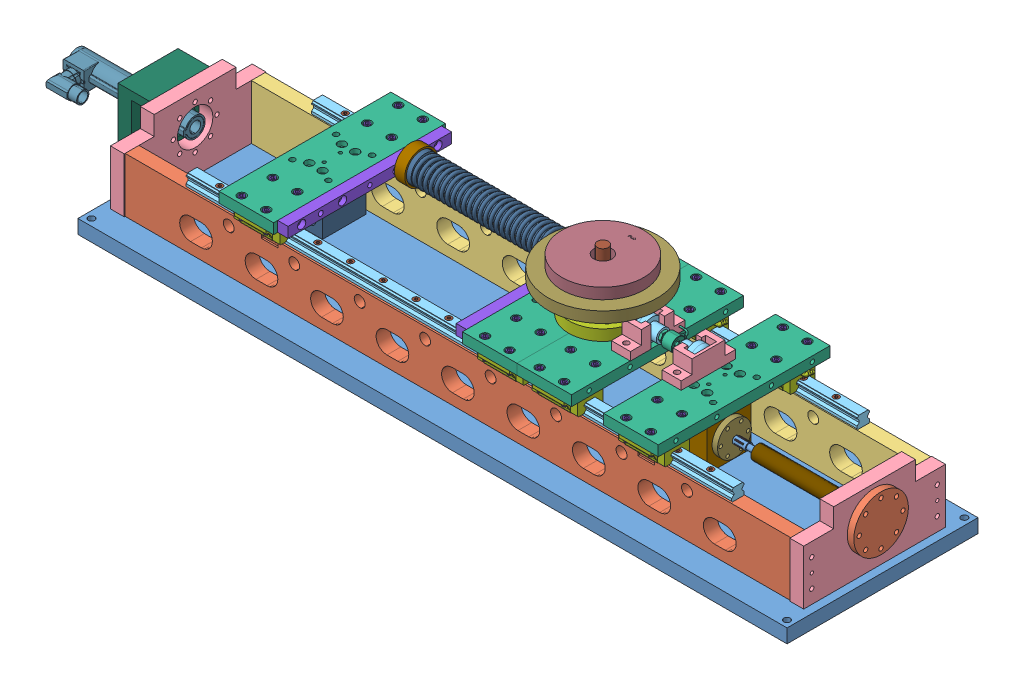
SolidWorks assembly Montagem global 2, configuration Valor predeterminado. Lengths in mm.
Overall size (1476 290.42 350).
128 component instances, 38 part files, 138 mates.
Components (placement in the parent):
- Breadboard-1: Breadboard [Default] at (-231.8815 -89.5152 1800) size (1800 58 900) (hidden)
- Base_global-1: Base_global [Valor predeterminado] at (-456.8815 -71.8152 1800) x (0 0 1) z (-1 0 0) size (350 25.4 1300)
- Lateral_comunha-1: Lateral_comunha [Valor predeterminado] at (-456.8815 -9.1152 1913) x (0 0 -1) z (1 0 0) size (25.4 100 1220)
- Lateral_semunha-1: Lateral_semunha [Valor predeterminado] at (-456.8815 -9.1152 1687) x (0 0 1) z (-1 0 0) size (25.4 100 1220)
- Cantoneira-1: Cantoneira [Valor predeterminado] at (-1079.5815 20.8848 1800) x (0 0 1) z (-1 0 0) size (260 135 25.4)
- Cantoneira-2: Cantoneira [Valor predeterminado] at (165.8185 20.8848 1800) x (0 0 1) z (-1 0 0) size (260 135 25.4)
- KR25 trilho1000-1: KR25 trilho1000 [Valor predeterminado] at (43.1185 42.034 1696.3931) x (0 1 0) z (-1 0 0) size (21.9 23 1000)
- KR25 trilho1000-2: KR25 trilho1000 [Valor predeterminado] at (43.1365 42.034 1926.3931) x (0 1 0) z (-1 0 0) size (21.9 23 1000)
- Montangem_atuador_linear-1: Montangem_atuador_linear [Valor predeterminado] at (-570.0811 33.0421 1784.6923) x (0 0 -1) z (1 0 0) size (315 119.02 108.05)
  - Montagem_plataforma_patins-1: Montagem_plataforma_patins [Valor predeterminado] at (20.5344 58.2954 310) size (315 49.52 108.05)
    - Plataforma-1: Plataforma [Valor predeterminado] at (-35.8421 -14.4528 149.5555) size (315 19.02 100)
    - KRH25-FL-N-Z0-1: KRH25-FL-N-Z0 [Valor predeterminado] at (79.1579 -44.9528 191.5555) x (0 0 -1) z (0 1 0) size (96 70 30.5)
    - KRH25-FL-N-Z0-2: KRH25-FL-N-Z0 [Valor predeterminado] at (-150.8421 -44.9528 107.5055) x (0 0 1) z (0 1 0) size (96 70 30.5)
    - Allen_M6x30-1: Allen_M6x30 [Valor predeterminado] at (107.6579 -33.4328 127.0555) x (1 0 0) z (0 1 0) size (10 10 38)
    - Allen_M6x30-2: Allen_M6x30 [Valor predeterminado] at (107.6579 -33.4328 172.0555) x (1 0 0) z (0 1 0) size (10 10 38)
    - Allen_M6x30-3: Allen_M6x30 [Valor predeterminado] at (-179.3421 -33.4328 172.0055) x (1 0 0) z (0 1 0) size (10 10 38)
    - Allen_M6x30-4: Allen_M6x30 [Valor predeterminado] at (-122.3421 -33.4328 172.0055) x (1 0 0) z (0 1 0) size (10 10 38)
    - Allen_M6x30-5: Allen_M6x30 [Valor predeterminado] at (-179.3421 -33.4328 127.0055) x (1 0 0) z (0 1 0) size (10 10 38)
    - Allen_M6x30-6: Allen_M6x30 [Valor predeterminado] at (-122.3421 -33.4328 127.0055) x (1 0 0) z (0 1 0) size (10 10 38)
    - Allen_M6x30-7: Allen_M6x30 [Valor predeterminado] at (50.6579 -33.4328 127.0555) x (1 0 0) z (0 1 0) size (10 10 38)
    - Allen_M6x30-8: Allen_M6x30 [Valor predeterminado] at (50.6579 -33.4328 172.0555) x (1 0 0) z (0 1 0) size (10 10 38)
  - Bloco_transmissão-1: Bloco_transmissão [Valor predeterminado] at (-15.3077 -14.7573 459.5555) size (80 100 44.45)
- Montagem_plataforma_patins-1: Montagem_plataforma_patins [Valor predeterminado] at (-219.97 91.3376 1835.8421) x (0 0 1) z (-1 0 0) size (315 49.52 108.05)
  - Plataforma-1: Plataforma [Valor predeterminado] at (-35.8421 -14.4528 149.5555) size (315 19.02 100)
  - KRH25-FL-N-Z0-1: KRH25-FL-N-Z0 [Valor predeterminado] at (79.1579 -44.9528 191.5555) x (0 0 -1) z (0 1 0) size (96 70 30.5)
  - KRH25-FL-N-Z0-2: KRH25-FL-N-Z0 [Valor predeterminado] at (-150.8421 -44.9528 107.5055) x (0 0 1) z (0 1 0) size (96 70 30.5)
  - Allen_M6x30-1: Allen_M6x30 [Valor predeterminado] at (107.6579 -33.4328 127.0555) x (1 0 0) z (0 1 0) size (10 10 38)
  - Allen_M6x30-2: Allen_M6x30 [Valor predeterminado] at (107.6579 -33.4328 172.0555) x (1 0 0) z (0 1 0) size (10 10 38)
  - Allen_M6x30-3: Allen_M6x30 [Valor predeterminado] at (-179.3421 -33.4328 172.0055) x (1 0 0) z (0 1 0) size (10 10 38)
  - Allen_M6x30-4: Allen_M6x30 [Valor predeterminado] at (-122.3421 -33.4328 172.0055) x (1 0 0) z (0 1 0) size (10 10 38)
  - Allen_M6x30-5: Allen_M6x30 [Valor predeterminado] at (-179.3421 -33.4328 127.0055) x (1 0 0) z (0 1 0) size (10 10 38)
  - Allen_M6x30-6: Allen_M6x30 [Valor predeterminado] at (-122.3421 -33.4328 127.0055) x (1 0 0) z (0 1 0) size (10 10 38)
  - Allen_M6x30-7: Allen_M6x30 [Valor predeterminado] at (50.6579 -33.4328 127.0555) x (1 0 0) z (0 1 0) size (10 10 38)
  - Allen_M6x30-8: Allen_M6x30 [Valor predeterminado] at (50.6579 -33.4328 172.0555) x (1 0 0) z (0 1 0) size (10 10 38)
- Montagem_plataforma_patins-2: Montagem_plataforma_patins [Valor predeterminado] at (-119.97 91.3376 1835.8421) x (0 0 1) z (-1 0 0) size (315 49.52 108.05)
  - Plataforma-1: Plataforma [Valor predeterminado] at (-35.8421 -14.4528 149.5555) size (315 19.02 100)
  - KRH25-FL-N-Z0-1: KRH25-FL-N-Z0 [Valor predeterminado] at (79.1579 -44.9528 191.5555) x (0 0 -1) z (0 1 0) size (96 70 30.5)
  - KRH25-FL-N-Z0-2: KRH25-FL-N-Z0 [Valor predeterminado] at (-150.8421 -44.9528 107.5055) x (0 0 1) z (0 1 0) size (96 70 30.5)
  - Allen_M6x30-1: Allen_M6x30 [Valor predeterminado] at (107.6579 -33.4328 127.0555) x (1 0 0) z (0 1 0) size (10 10 38)
  - Allen_M6x30-2: Allen_M6x30 [Valor predeterminado] at (107.6579 -33.4328 172.0555) x (1 0 0) z (0 1 0) size (10 10 38)
  - Allen_M6x30-3: Allen_M6x30 [Valor predeterminado] at (-179.3421 -33.4328 172.0055) x (1 0 0) z (0 1 0) size (10 10 38)
  - Allen_M6x30-4: Allen_M6x30 [Valor predeterminado] at (-122.3421 -33.4328 172.0055) x (1 0 0) z (0 1 0) size (10 10 38)
  - Allen_M6x30-5: Allen_M6x30 [Valor predeterminado] at (-179.3421 -33.4328 127.0055) x (1 0 0) z (0 1 0) size (10 10 38)
  - Allen_M6x30-6: Allen_M6x30 [Valor predeterminado] at (-122.3421 -33.4328 127.0055) x (1 0 0) z (0 1 0) size (10 10 38)
  - Allen_M6x30-7: Allen_M6x30 [Valor predeterminado] at (50.6579 -33.4328 127.0555) x (1 0 0) z (0 1 0) size (10 10 38)
  - Allen_M6x30-8: Allen_M6x30 [Valor predeterminado] at (50.6579 -33.4328 172.0555) x (1 0 0) z (0 1 0) size (10 10 38)
- Montagem_travamento-1: Montagem_travamento [Valor predeterminado] at (-356.05 51.4223 1850.3971) x (0 0 1) z (-1 0 0) size (315 99.02 108.05)
  - Montagem_plataforma_patins-1: Montagem_plataforma_patins [Valor predeterminado] at (-14.5551 39.9153 310) size (315 49.52 108.05)
    - Plataforma-1: Plataforma [Valor predeterminado] at (-35.8421 -14.4528 149.5555) size (315 19.02 100)
    - KRH25-FL-N-Z0-1: KRH25-FL-N-Z0 [Valor predeterminado] at (79.1579 -44.9528 191.5555) x (0 0 -1) z (0 1 0) size (96 70 30.5)
    - KRH25-FL-N-Z0-2: KRH25-FL-N-Z0 [Valor predeterminado] at (-150.8421 -44.9528 107.5055) x (0 0 1) z (0 1 0) size (96 70 30.5)
    - Allen_M6x30-1: Allen_M6x30 [Valor predeterminado] at (107.6579 -33.4328 127.0555) x (1 0 0) z (0 1 0) size (10 10 38)
    - Allen_M6x30-2: Allen_M6x30 [Valor predeterminado] at (107.6579 -33.4328 172.0555) x (1 0 0) z (0 1 0) size (10 10 38)
    - Allen_M6x30-3: Allen_M6x30 [Valor predeterminado] at (-179.3421 -33.4328 172.0055) x (1 0 0) z (0 1 0) size (10 10 38)
    - Allen_M6x30-4: Allen_M6x30 [Valor predeterminado] at (-122.3421 -33.4328 172.0055) x (1 0 0) z (0 1 0) size (10 10 38)
    - Allen_M6x30-5: Allen_M6x30 [Valor predeterminado] at (-179.3421 -33.4328 127.0055) x (1 0 0) z (0 1 0) size (10 10 38)
    - Allen_M6x30-6: Allen_M6x30 [Valor predeterminado] at (-122.3421 -33.4328 127.0055) x (1 0 0) z (0 1 0) size (10 10 38)
    - Allen_M6x30-7: Allen_M6x30 [Valor predeterminado] at (50.6579 -33.4328 127.0555) x (1 0 0) z (0 1 0) size (10 10 38)
    - Allen_M6x30-8: Allen_M6x30 [Valor predeterminado] at (50.6579 -33.4328 172.0555) x (1 0 0) z (0 1 0) size (10 10 38)
  - Bloco_travamento-1: Bloco_travamento [Valor predeterminado] at (-50.3971 -14.5375 459.5555) size (80 80 44.45)
- Allen M7x40-1: Allen M7x40 [Valor predeterminado] at (-6.8635 13.3848 1915) x (-0.069412 0 -0.997588) z (0.997588 0 -0.069412) size (11 49.5 11)
- Allen M7x40-2: Allen M7x40 [Valor predeterminado] at (-846.8815 13.2848 1685) x (-0.069412 0 -0.997588) z (0.997588 0 -0.069412) size (11 49.5 11)
- Allen M7x40-3: Allen M7x40 [Valor predeterminado] at (-546.8635 13.2848 1915) x (-0.069412 0 -0.997588) z (0.997588 0 -0.069412) size (11 49.5 11)
- Allen M7x40-4: Allen M7x40 [Valor predeterminado] at (-486.8635 13.2848 1915) x (-0.069412 0 -0.997588) z (0.997588 0 -0.069412) size (11 49.5 11)
- Allen M7x40-5: Allen M7x40 [Valor predeterminado] at (-426.8635 13.2848 1915) x (-0.069412 0 -0.997588) z (0.997588 0 -0.069412) size (11 49.5 11)
- Allen M7x40-6: Allen M7x40 [Valor predeterminado] at (-366.8635 13.2848 1915) x (-0.069412 0 -0.997588) z (0.997588 0 -0.069412) size (11 49.5 11)
- Allen M7x40-7: Allen M7x40 [Valor predeterminado] at (-606.8635 13.2848 1915) x (-0.069412 0 -0.997588) z (0.997588 0 -0.069412) size (11 49.5 11)
- Allen M7x40-8: Allen M7x40 [Valor predeterminado] at (-666.8815 13.2848 1685) x (-0.069412 0 -0.997588) z (0.997588 0 -0.069412) size (11 49.5 11)
- Allen M7x40-9: Allen M7x40 [Valor predeterminado] at (-666.8635 13.2848 1915) x (-0.069412 0 -0.997588) z (0.997588 0 -0.069412) size (11 49.5 11)
- Allen M7x40-10: Allen M7x40 [Valor predeterminado] at (-66.8815 13.2848 1685) x (-0.069412 0 -0.997588) z (0.997588 0 -0.069412) size (11 49.5 11)
- Allen M7x40-11: Allen M7x40 [Valor predeterminado] at (-786.8635 13.2848 1915) x (-0.069412 0 -0.997588) z (0.997588 0 -0.069412) size (11 49.5 11)
- Allen M7x40-12: Allen M7x40 [Valor predeterminado] at (-246.8815 13.2848 1685) x (-0.069412 0 -0.997588) z (0.997588 0 -0.069412) size (11 49.5 11)
- Allen M7x40-13: Allen M7x40 [Valor predeterminado] at (-306.8635 13.2848 1915) x (-0.069412 0 -0.997588) z (0.997588 0 -0.069412) size (11 49.5 11)
- Allen M7x40-14: Allen M7x40 [Valor predeterminado] at (-6.8815 13.2848 1685) x (-0.069412 0 -0.997588) z (0.997588 0 -0.069412) size (11 49.5 11)
- Allen M7x40-15: Allen M7x40 [Valor predeterminado] at (-426.8815 13.2848 1685) x (-0.069412 0 -0.997588) z (0.997588 0 -0.069412) size (11 49.5 11)
- Allen M7x40-16: Allen M7x40 [Valor predeterminado] at (-186.8815 13.2848 1685) x (-0.069412 0 -0.997588) z (0.997588 0 -0.069412) size (11 49.5 11)
- Allen M7x40-17: Allen M7x40 [Valor predeterminado] at (-246.8635 13.2848 1915) x (-0.069412 0 -0.997588) z (0.997588 0 -0.069412) size (11 49.5 11)
- Allen M7x40-18: Allen M7x40 [Valor predeterminado] at (-186.8635 13.2848 1915) x (-0.069412 0 -0.997588) z (0.997588 0 -0.069412) size (11 49.5 11)
- Allen M7x40-19: Allen M7x40 [Valor predeterminado] at (-126.8635 13.2848 1915) x (-0.069412 0 -0.997588) z (0.997588 0 -0.069412) size (11 49.5 11)
- Allen M7x40-20: Allen M7x40 [Valor predeterminado] at (-846.8635 13.2848 1915) x (-0.069412 0 -0.997588) z (0.997588 0 -0.069412) size (11 49.5 11)
- Allen M7x40-21: Allen M7x40 [Valor predeterminado] at (-306.8815 13.2848 1685) x (-0.069412 0 -0.997588) z (0.997588 0 -0.069412) size (11 49.5 11)
- Allen M7x40-22: Allen M7x40 [Valor predeterminado] at (-906.8635 13.2848 1915) x (-0.069412 0 -0.997588) z (0.997588 0 -0.069412) size (11 49.5 11)
- Allen M7x40-23: Allen M7x40 [Valor predeterminado] at (-126.8815 13.2848 1685) x (-0.069412 0 -0.997588) z (0.997588 0 -0.069412) size (11 49.5 11)
- Allen M7x40-24: Allen M7x40 [Valor predeterminado] at (-906.8815 13.2848 1685) x (-0.069412 0 -0.997588) z (0.997588 0 -0.069412) size (11 49.5 11)
- Allen M7x40-25: Allen M7x40 [Valor predeterminado] at (-786.8815 13.2848 1685) x (-0.069412 0 -0.997588) z (0.997588 0 -0.069412) size (11 49.5 11)
- Allen M7x40-26: Allen M7x40 [Valor predeterminado] at (-366.8815 13.2848 1685) x (-0.069412 0 -0.997588) z (0.997588 0 -0.069412) size (11 49.5 11)
- Allen M7x40-27: Allen M7x40 [Valor predeterminado] at (-726.8815 13.2848 1685) x (-0.069412 0 -0.997588) z (0.997588 0 -0.069412) size (11 49.5 11)
- Allen M7x40-28: Allen M7x40 [Valor predeterminado] at (-66.8635 13.2848 1915) x (-0.069412 0 -0.997588) z (0.997588 0 -0.069412) size (11 49.5 11)
- Allen M7x40-29: Allen M7x40 [Valor predeterminado] at (-606.8815 13.2848 1685) x (-0.069412 0 -0.997588) z (0.997588 0 -0.069412) size (11 49.5 11)
- Allen M7x40-30: Allen M7x40 [Valor predeterminado] at (-726.8635 13.2848 1915) x (-0.069412 0 -0.997588) z (0.997588 0 -0.069412) size (11 49.5 11)
- Allen M7x40-31: Allen M7x40 [Valor predeterminado] at (-546.8815 13.2848 1685) x (-0.069412 0 -0.997588) z (0.997588 0 -0.069412) size (11 49.5 11)
- Allen M7x40-32: Allen M7x40 [Valor predeterminado] at (-486.8815 13.2986 1685) x (-0.069412 0 -0.997588) z (0.997588 0 -0.069412) size (11 49.5 11)
- Flange_Acoplamento_FK-1: Flange_Acoplamento_FK [Valor predeterminado] at (-83.3005 18.2848 1800) x (0 0 1) z (-1 0 0) size (62 62 10)
- 2061_FK_M6____asm_0_0_-1: 2061_FK_M6____asm_0_0_ [Standard] at (-73.7005 18.2848 1800) x (0 0.921332 0.388776) z (-1 0 0) size (13 15.67 37)
  - 2061_FK_M6____GE_-1: 2061_FK_M6____GE_ [Standard] at origin size (13 15.67 14.5)
  - 2061_FK_M6____0BO_-1: 2061_FK_M6____0BO_ [Standard] at (0 0 3.1) x (-1 0 0) z (0 0 1) size (8 8 24.5)
  - DIN_439_B___M6_F_-1: DIN_439_B___M6_F_ [Standard] at (0 0 6.3) x (1 0 0) z (0 1 0) size (10 3.2 11.55) (hidden)
  - 2061_FK_M6____BU_-1: 2061_FK_M6____BU_ [Standard] at (0 0 -10.4) x (1 0 0) z (0 0 -1) size (10 10 11.5)
  - 2061_FK_M6____MU_-1: 2061_FK_M6____MU_ [Standard] at (0 0 -17.5) size (13 14.5 3)
  - 2061_FK_M6____KG_-1: 2061_FK_M6____KG_ [Standard] at (0 0 -4) size (8.8 8.8 2)
  - 2061_FK_M6____KG_-2: 2061_FK_M6____KG_ [Standard] at (0 0 -8.4) x (1 0 0) z (0 0 -1) size (8.8 8.8 2)
- Cilindro_hidraulico-1: Cilindro_hidraulico [Valor predeterminado] at (190.09 -90.1122 1935.1975) x (0.173648 0.818832 -0.547138) z (0.984808 -0.144382 0.096475) size (80.99 75.67 284.21)
  - INTF_1_2-2: INTF_1_2 [Valor predeterminado] at (127.4874 -176.1214 -201.3756) size (70.31 75.67 209.33)
  - INTF_1_8-2: INTF_1_8 [Valor predeterminado] at (14.303 -53.5846 -156.297) x (0.077983 -0.983609 0.162577) z (0.162577 0.173437 0.971333) size (39.86 20 157.48)
- fixação cilidro-1: fixação cilidro [Valor predeterminado] at (148.5185 18.2848 1800) x (0 1 0) z (1 0 0) size (100 100 42)
- eixo-1: eixo [Valor predeterminado] at (158.5185 18.2848 1801.5) x (0 0 -1) z (1 0 0) size (60 8 8)
- Montagem_célula_de_carga-1: Montagem_célula_de_carga [Valor predeterminado] at (-336.5256 100.2065 1820.2128) x (0 0 -1) z (1 0 0) size (100 52.27 234.41)
  - Alojamento_acomplamento-1: Alojamento_acomplamento [Valor predeterminado] at (20.2128 15.6982 82.5001) size (100 39.97 35)
  - Alojamento_acomplamento-2: Alojamento_acomplamento [Valor predeterminado] at (20.2128 15.6982 210.5) x (-1 0 0) z (0 0 -1) size (100 39.97 35)
  - Acomplamento_celula_mola-1: Acomplamento_celula_mola [Valor predeterminado] at (20.2128 15.6982 107.5001) x (-0.923728 -0.383049 0) z (0 0 -1) size (40 40 40)
  - Acomplamento_celula_mola-2: Acomplamento_celula_mola [Valor predeterminado] at (20.2128 15.6982 185.5) x (-1 0 0) z (0 0 1) size (40 40 40)
  - U9C_G_5kN-1: U9C_G_5kN [Valor predeterminado] at (20.2128 15.6982 137.5001) size (45.3 26.62 60.01)
- Junção carrinhos-1: Junção carrinhos [Valor predeterminado] at (-319.5255 95.9048 1800) x (0 1 0) z (-1 0 0) size (55 125 125)
- suporte mola-1: suporte mola [Valor predeterminado] at (-419.5255 83.2048 1800) x (-1 0 0) z (0 0 -1) size (19.02 19.02 300)
- suporte mola-2: suporte mola [Valor predeterminado] at (-765.6055 83.2048 1800) size (19.02 19.02 300)
- Montagem mola-1: Montagem mola [Valor predeterminado] at (-349.5991 92.6763 1840.6726) x (0 -0.466424 0.884562) z (-1 0 0) size (78.41 78.41 308.04)
  - Suporte_mola-1: Suporte_mola [Valor predeterminado] at (-99.3897 -59.5088 88.9464) x (0.923728 0.383049 0) z (0 0 1) size (60 60 19.02)
  - Mola 30 cm-1: Mola 30 cm [Valor predeterminado] at (-99.3897 -59.5088 377.9664) x (-0.923728 -0.383049 0) z (0.383049 -0.923728 0) size (52.37 285 54.99)
  - Suporte_mola-2: Suporte_mola [Valor predeterminado] at (-99.3897 -59.5088 396.9864) x (-0.923728 -0.383049 0) z (0 0 -1) size (60 60 19.02)
- Torre_central-1: Torre_central [Valor predeterminado] at (-319.5255 125.9048 1800) x (0.839805 0 0.542888) z (-0.542888 0 0.839805) size (20 80 20)
- Peso 5kg-1: Peso 5kg [Valor predeterminado] at (-319.5255 150.9048 1800) size (200 20 200)
- Peso 2kg-1: Peso 2kg [Valor predeterminado] at (-319.5255 170.9048 1800) size (150 20 150)
- LinMot-1: LinMot [Valor predeterminado] at (-1066.8815 18.2848 1800) x (0 1 0) z (1 0 0) size (38 87 216)
- Fixação LinMot-1: Fixação LinMot [Valor predeterminado] at (-1152.2815 18.2848 1800) x (0 1 0) z (1 0 0) size (110 110 60)
- Montagem encoder-1: Montagem encoder [Valor predeterminado] at (-819.4837 149.4848 1999.24) x (0 0 -1) z (0 -1 0) size (64 69.66 180)
  - Suporte encoder-1: Suporte encoder [Valor predeterminado] at (7.94 0.2323 64) size (60 46 20) (hidden)
  - LM10-readhead-1: LM10-readhead [Default] at (40.94 20.7323 64) x (0 -1 0) z (0 0 -1) size (50.16 24 14.58) (hidden)
  - Suporte encoder 2-1: Suporte encoder 2 [Valor predeterminado] at (-10.56 -0.7677 234) x (0 1 0) z (-1 0 0) size (60 150 25) (hidden)
Mates (geometry in assembly coordinates):
- Coincidente1: coincident anti-aligned: plane of Breadboard-1 through (655.6185 -84.5152 2237.5) normal (0 1 0); plane of Base_global-1 through (-1046.8815 -84.5152 1668) normal (0 -1 0)
- Coincidente5: coincident anti-aligned: plane of Base_global-1 through (-1046.8815 -59.1152 1668) normal (0 1 0); plane of Lateral_semunha-1 through (-1066.8815 -59.1152 1677) normal (0 -1 0)
- Coincidente6: coincident anti-aligned: plane of Base_global-1 through (-1046.8815 -59.1152 1668) normal (0 1 0); plane of Lateral_comunha-1 through (153.1185 -59.1152 1923) normal (0 -1 0)
- Concêntrico1: concentric aligned: circle of Base_global-1; circle of Lateral_comunha-1
- Concêntrico2: concentric aligned: circle of Base_global-1; circle of Lateral_comunha-1
- Concêntrico3: concentric aligned: circle of Base_global-1; circle of Lateral_semunha-1
- Concêntrico4: concentric aligned: circle of Base_global-1; circle of Lateral_semunha-1
- Concêntrico5: concentric aligned: circle of Lateral_comunha-1; circle of Cantoneira-1
- Concêntrico6: concentric aligned: circle of Lateral_semunha-1; circle of Cantoneira-1
- Coincidente9: coincident anti-aligned: plane of Lateral_semunha-1 through (-1066.8815 -9.1152 1687) normal (-1 0 0); plane of Cantoneira-1 through (-1066.8815 20.8848 1800) normal (1 0 0)
- Concêntrico7: concentric anti-aligned: circle of Lateral_comunha-1; circle of Cantoneira-2
- Concêntrico8: concentric anti-aligned: circle of Lateral_semunha-1; circle of Cantoneira-2
- Coincidente12: coincident anti-aligned: plane of Lateral_semunha-1 through (153.1185 -9.1152 1687) normal (1 0 0); plane of Cantoneira-2 through (153.1185 20.8848 1800) normal (-1 0 0)
- Concêntrico16: concentric anti-aligned: cylinder of Cantoneira-2 through (281.5185 18.2848 1800) axis (-1 0 0) radius 32.5; circle of Montangem_atuador_linear-1/Bloco_transmissão-1
- Coincidente25: coincident anti-aligned: plane of Lateral_comunha-1 through (153.1185 40.8848 1923) normal (0 1 0); plane of KR25 trilho1000-2 through (-956.8635 40.8848 1905) normal (0 -1 0)
- Concêntrico17: concentric aligned: circle of Lateral_comunha-1; cylinder of KR25 trilho1000-2 through (-6.8635 53.8848 1915) axis (0 1 0) radius 5.5
- Concêntrico18: concentric aligned: circle of Lateral_comunha-1; circle of KR25 trilho1000-2
- Coincidente26: coincident anti-aligned: plane of Lateral_semunha-1 through (-1066.8815 40.8848 1677) normal (0 1 0); plane of KR25 trilho1000-1 through (-956.8815 40.8848 1675) normal (0 -1 0)
- Concêntrico19: concentric aligned: circle of Lateral_semunha-1; circle of KR25 trilho1000-1
- Concêntrico20: concentric aligned: circle of Lateral_semunha-1; circle of KR25 trilho1000-1
- Coincidente27: coincident anti-aligned: plane of Montangem_atuador_linear-1/Montagem_plataforma_patins-1/KRH25-FL-N-Z0-1 through (-81.5255 62.7848 1676.4913) normal (0 -1 0); plane of KR25 trilho1000-1 through (-956.8815 62.7848 1693.5087) normal (0 1 0)
- Concêntrico21: concentric aligned: circle of KR25 trilho1000-2; circle of Parafuso_trilho_TR25-1
- Coincidente29: coincident aligned: plane of KR25 trilho1000-2 through (-6.8635 53.8848 1915) normal (0 1 0); circle of Parafuso_trilho_TR25-1
- Coincidente30: coincident aligned: circle of KR25 trilho1000-2; circle of Parafuso_trilho_TR25-28
- Concêntrico23: concentric aligned: circle of KR25 trilho1000-2; circle of Parafuso_trilho_TR25-28
- Concêntrico24: concentric anti-aligned: cylinder of KR25 trilho1000-2 through (-126.8635 53.8848 1915) axis (0 1 0) radius 5.5; cylinder of Allen M7x40-19 through (-126.8635 62.7848 1915) axis (0 -1 0) radius 5.5
- Concêntrico25: concentric anti-aligned: cylinder of KR25 trilho1000-2 through (-186.8635 53.8848 1915) axis (0 1 0) radius 5.5; cylinder of Allen M7x40-18 through (-186.8635 62.7848 1915) axis (0 -1 0) radius 5.5
- Concêntrico26: concentric anti-aligned: circle of KR25 trilho1000-2; cylinder of Allen M7x40-17 through (-246.8635 62.7848 1915) axis (0 -1 0) radius 5.5
- Coincidente33: coincident aligned: plane of KR25 trilho1000-2 through (-956.8635 62.7848 1923.5087) normal (0 1 0); plane of Allen M7x40-19 through (-126.8635 62.7848 1915) normal (0 1 0)
- Coincidente34: coincident aligned: plane of KR25 trilho1000-2 through (-956.8635 62.7848 1923.5087) normal (0 1 0); plane of Allen M7x40-18 through (-186.8635 62.7848 1915) normal (0 1 0)
- Coincidente35: coincident aligned: plane of KR25 trilho1000-2 through (-956.8635 62.7848 1923.5087) normal (0 1 0); plane of Allen M7x40-17 through (-246.8635 62.7848 1915) normal (0 1 0)
- Coincidente36: coincident aligned: plane of KR25 trilho1000-2 through (-956.8635 62.7848 1923.5087) normal (0 1 0); plane of Allen M7x40-13 through (-306.8635 62.7848 1915) normal (0 1 0)
- Coincidente37: coincident aligned: plane of KR25 trilho1000-2 through (-956.8635 62.7848 1923.5087) normal (0 1 0); circle of Parafuso_trilho_TR25-6
- Coincidente38: coincident aligned: plane of KR25 trilho1000-2 through (-956.8635 62.7848 1923.5087) normal (0 1 0); circle of Parafuso_trilho_TR25-5
- Coincidente39: coincident aligned: plane of KR25 trilho1000-2 through (-956.8635 62.7848 1923.5087) normal (0 1 0); plane of Allen M7x40-4 through (-486.8635 62.7848 1915) normal (0 1 0)
- Coincidente40: coincident aligned: plane of KR25 trilho1000-2 through (-956.8635 62.7848 1923.5087) normal (0 1 0); circle of Parafuso_trilho_TR25-3
- Concêntrico28: concentric aligned: circle of KR25 trilho1000-2; circle of Parafuso_trilho_TR25-6
- Concêntrico29: concentric aligned: circle of KR25 trilho1000-2; circle of Parafuso_trilho_TR25-5
- Concêntrico30: concentric aligned: circle of KR25 trilho1000-2; circle of Parafuso_trilho_TR25-4
- Concêntrico31: concentric aligned: circle of KR25 trilho1000-2; circle of Parafuso_trilho_TR25-3
- Coincidente48: coincident aligned: plane of KR25 trilho1000-2 through (-956.8635 62.7848 1923.5087) normal (0 1 0); circle of Parafuso_trilho_TR25-7
- Coincidente49: coincident aligned: plane of KR25 trilho1000-2 through (-956.8635 62.7848 1923.5087) normal (0 1 0); circle of Parafuso_trilho_TR25-9
- Coincidente50: coincident aligned: plane of KR25 trilho1000-2 through (-956.8635 62.7848 1923.5087) normal (0 1 0); circle of Parafuso_trilho_TR25-30
- Coincidente51: coincident aligned: plane of KR25 trilho1000-2 through (-956.8635 62.7848 1923.5087) normal (0 1 0); plane of Allen M7x40-11 through (-786.8635 62.7848 1915) normal (0 1 0)
- Coincidente52: coincident aligned: plane of KR25 trilho1000-2 through (-956.8635 62.7848 1923.5087) normal (0 1 0); circle of Parafuso_trilho_TR25-22
- Coincidente53: coincident aligned: plane of KR25 trilho1000-2 through (-956.8635 62.7848 1923.5087) normal (0 1 0); circle of Parafuso_trilho_TR25-20
- Concêntrico32: concentric aligned: circle of KR25 trilho1000-2; circle of Parafuso_trilho_TR25-30
- Concêntrico33: concentric aligned: circle of KR25 trilho1000-2; circle of Parafuso_trilho_TR25-9
- Concêntrico34: concentric aligned: circle of KR25 trilho1000-2; circle of Parafuso_trilho_TR25-7
- Concêntrico35: concentric aligned: circle of KR25 trilho1000-2; circle of Parafuso_trilho_TR25-22
- Concêntrico36: concentric aligned: circle of KR25 trilho1000-2; circle of Parafuso_trilho_TR25-20
- Concêntrico37: concentric aligned: circle of KR25 trilho1000-2; circle of Parafuso_trilho_TR25-11
- Coincidente60: coincident aligned: plane of KR25 trilho1000-1 through (-956.8815 62.7848 1693.5087) normal (0 1 0); circle of Parafuso_trilho_TR25-14
- Coincidente61: coincident aligned: plane of KR25 trilho1000-1 through (-956.8815 62.7848 1693.5087) normal (0 1 0); circle of Parafuso_trilho_TR25-10
- Coincidente62: coincident aligned: plane of KR25 trilho1000-1 through (-956.8815 62.7848 1693.5087) normal (0 1 0); circle of Parafuso_trilho_TR25-23
- Coincidente63: coincident aligned: plane of KR25 trilho1000-1 through (-956.8815 62.7848 1693.5087) normal (0 1 0); circle of Parafuso_trilho_TR25-16
- Coincidente64: coincident aligned: plane of KR25 trilho1000-1 through (-956.8815 62.7848 1693.5087) normal (0 1 0); circle of Parafuso_trilho_TR25-12
- Coincidente65: coincident aligned: plane of KR25 trilho1000-1 through (-956.8815 62.7848 1693.5087) normal (0 1 0); circle of Parafuso_trilho_TR25-21
- Concêntrico38: concentric anti-aligned: cylinder of KR25 trilho1000-1 through (-6.8815 53.8848 1685) axis (0 1 0) radius 5.5; cylinder of Allen M7x40-14 through (-6.8815 62.7848 1685) axis (0 -1 0) radius 5.5
- Concêntrico39: concentric anti-aligned: cylinder of KR25 trilho1000-1 through (-66.8815 53.8848 1685) axis (0 1 0) radius 5.5; cylinder of Allen M7x40-10 through (-66.8815 62.7848 1685) axis (0 -1 0) radius 5.5
- Concêntrico40: concentric anti-aligned: circle of KR25 trilho1000-1; cylinder of Allen M7x40-23 through (-126.8815 62.7848 1685) axis (0 -1 0) radius 5.5
- Concêntrico41: concentric anti-aligned: circle of KR25 trilho1000-1; cylinder of Allen M7x40-16 through (-186.8815 62.7848 1685) axis (0 -1 0) radius 5.5
- Concêntrico42: concentric aligned: circle of KR25 trilho1000-1; circle of Parafuso_trilho_TR25-12
- Concêntrico43: concentric aligned: circle of KR25 trilho1000-1; circle of Parafuso_trilho_TR25-21
- Coincidente70: coincident aligned: plane of KR25 trilho1000-1 through (-956.8815 62.7848 1693.5087) normal (0 1 0); circle of Parafuso_trilho_TR25-29
- Coincidente71: coincident aligned: plane of KR25 trilho1000-1 through (-956.8815 62.7848 1693.5087) normal (0 1 0); plane of Allen M7x40-8 through (-666.8815 62.7848 1685) normal (0 1 0)
- Coincidente72: coincident aligned: plane of KR25 trilho1000-1 through (-956.8815 62.7848 1693.5087) normal (0 1 0); circle of Parafuso_trilho_TR25-31
- Coincidente73: coincident aligned: plane of KR25 trilho1000-1 through (-956.8815 62.7848 1693.5087) normal (0 1 0); circle of Parafuso_trilho_TR25-15
- Coincidente74: coincident aligned: plane of KR25 trilho1000-1 through (-956.8815 62.7848 1693.5087) normal (0 1 0); plane of Allen M7x40-26 through (-366.8815 62.7848 1685) normal (0 1 0)
- Coincidente75: coincident aligned: plane of KR25 trilho1000-1 through (-956.8815 62.7848 1693.5087) normal (0 1 0); circle of Parafuso_trilho_TR25-27
- Coincidente76: coincident aligned: plane of KR25 trilho1000-1 through (-956.8815 62.7848 1693.5087) normal (0 1 0); plane of Allen M7x40-25 through (-786.8815 62.7848 1685) normal (0 1 0)
- Coincidente77: coincident aligned: plane of KR25 trilho1000-1 through (-956.8815 62.7848 1693.5087) normal (0 1 0); plane of Allen M7x40-24 through (-906.8815 62.7848 1685) normal (0 1 0)
- Concêntrico44: concentric anti-aligned: cylinder of KR25 trilho1000-1 through (-366.8815 53.8848 1685) axis (0 1 0) radius 5.5; cylinder of Allen M7x40-26 through (-366.8815 62.7848 1685) axis (0 -1 0) radius 5.5
- Concêntrico45: concentric anti-aligned: cylinder of KR25 trilho1000-1 through (-426.8815 53.8848 1685) axis (0 1 0) radius 5.5; cylinder of Allen M7x40-15 through (-426.8815 62.7848 1685) axis (0 -1 0) radius 5.5
- Concêntrico46: concentric anti-aligned: cylinder of KR25 trilho1000-1 through (-486.8815 53.8848 1685) axis (0 1 0) radius 5.5; cylinder of Allen M7x40-32 through (-486.8815 62.7986 1685) axis (0 -1 0) radius 5.5
- Concêntrico47: concentric anti-aligned: cylinder of KR25 trilho1000-1 through (-546.8815 53.8848 1685) axis (0 1 0) radius 5.5; cylinder of Allen M7x40-31 through (-546.8815 62.7848 1685) axis (0 -1 0) radius 5.5
- Concêntrico48: concentric anti-aligned: cylinder of KR25 trilho1000-1 through (-606.8815 53.8848 1685) axis (0 1 0) radius 5.5; cylinder of Allen M7x40-29 through (-606.8815 62.7848 1685) axis (0 -1 0) radius 5.5
- Concêntrico49: concentric anti-aligned: cylinder of KR25 trilho1000-1 through (-666.8815 53.8848 1685) axis (0 1 0) radius 5.5; cylinder of Allen M7x40-8 through (-666.8815 62.7848 1685) axis (0 -1 0) radius 5.5
- Concêntrico50: concentric anti-aligned: circle of KR25 trilho1000-1; cylinder of Allen M7x40-27 through (-726.8815 62.7848 1685) axis (0 -1 0) radius 5.5
- Concêntrico51: concentric anti-aligned: cylinder of KR25 trilho1000-1 through (-786.8815 53.8848 1685) axis (0 1 0) radius 5.5; cylinder of Allen M7x40-25 through (-786.8815 62.7848 1685) axis (0 -1 0) radius 5.5
- Concêntrico52: concentric anti-aligned: circle of KR25 trilho1000-1; cylinder of Allen M7x40-24 through (-906.8815 62.7848 1685) axis (0 -1 0) radius 5.5
- Coincidente81: coincident aligned: plane of KR25 trilho1000-1 through (-956.8815 62.7848 1693.5087) normal (0 1 0); circle of Parafuso_trilho_TR25-2
- Concêntrico53: concentric aligned: circle of KR25 trilho1000-1; circle of Parafuso_trilho_TR25-2
- Concêntrico94: concentric anti-aligned: cylinder of KR25 trilho1000-2 through (-306.8635 53.8848 1915) axis (0 1 0) radius 5.5; cylinder of Allen M7x40-13 through (-306.8635 62.7848 1915) axis (0 -1 0) radius 5.5
- Coincidente89: coincident aligned: plane of KR25 trilho1000-2 through (-956.8635 62.7848 1923.5087) normal (0 1 0); plane of Allen M7x40-13 through (-306.8635 62.7848 1915) normal (0 1 0)
- Coincidente129: coincident anti-aligned: plane of KR25 trilho1000-2 through (-956.8635 50.7834 1922.7) normal (0 0 1); plane of Montagem_travamento-1/Montagem_plataforma_patins-1/KRH25-FL-N-Z0-1 through (-844.6055 50.7834 1922.7) normal (0 0 -1)
- Coincidente130: coincident anti-aligned: plane of KR25 trilho1000-2 through (-956.8635 62.7848 1923.5087) normal (0 1 0); plane of Montagem_travamento-1/Montagem_plataforma_patins-1/KRH25-FL-N-Z0-1 through (-844.6055 62.7848 1923.5087) normal (0 -1 0)
- Coincidente131: coincident anti-aligned: plane of KR25 trilho1000-2 through (-956.8635 50.7834 1922.7) normal (0 0 1); plane of Montagem_plataforma_patins-2/KRH25-FL-N-Z0-1 through (-298.5255 50.7834 1922.7) normal (0 0 -1)
- Coincidente132: coincident anti-aligned: plane of KR25 trilho1000-2 through (-956.8635 62.7848 1923.5087) normal (0 1 0); plane of Montagem_plataforma_patins-2/KRH25-FL-N-Z0-1 through (-298.5255 62.7848 1923.5087) normal (0 -1 0)
- Coincidente133: coincident anti-aligned: plane of KR25 trilho1000-2 through (-956.8635 50.7834 1922.7) normal (0 0 1); plane of Montagem_plataforma_patins-1/KRH25-FL-N-Z0-1 through (-398.5255 50.7834 1922.7) normal (0 0 -1)
- Coincidente134: coincident anti-aligned: plane of KR25 trilho1000-2 through (-956.8635 62.7848 1923.5087) normal (0 1 0); plane of Montagem_plataforma_patins-1/KRH25-FL-N-Z0-1 through (-398.5255 62.7848 1923.5087) normal (0 -1 0)
- Concêntrico107: concentric anti-aligned: cylinder of Montangem_atuador_linear-1/Bloco_transmissão-1 through (-132.7505 18.2848 1800) axis (1 0 0) radius 19; cylinder of Flange_Acoplamento_FK-1 through (-78.3005 18.2848 1800) axis (-1 0 0) radius 3
- Concêntrico108: concentric aligned: cylinder of Montangem_atuador_linear-1/Bloco_transmissão-1 through (-122.8005 39.9354 1812.5) axis (1 0 0) radius 3.3; circle of Flange_Acoplamento_FK-1
- Concêntrico109: concentric aligned: cylinder of Flange_Acoplamento_FK-1 through (-78.3005 18.2848 1800) axis (-1 0 0) radius 3; cylinder of 2061_FK_M6____asm_0_0_-1/2061_FK_M6____0BO_-1 through (-76.8005 18.2848 1800) axis (-1 0 0) radius 3
- Coincidente144: coincident anti-aligned: plane of Montangem_atuador_linear-1/Bloco_transmissão-1 through (-88.3005 18.2848 1800) normal (1 0 0); plane of Flange_Acoplamento_FK-1 through (-88.3005 18.2848 1800) normal (-1 0 0)
- Coincidente145: coincident aligned: circle of Flange_Acoplamento_FK-1; circle of 2061_FK_M6____asm_0_0_-1/2061_FK_M6____0BO_-1
- Concêntrico110: concentric aligned: cylinder of 2061_FK_M6____asm_0_0_-1/2061_FK_M6____BU_-1 through (-63.3005 18.2848 1800) axis (1 0 0) radius 2.4585; cylinder of Cilindro_hidraulico-1/INTF_1_8-2 through (-65.8005 18.2848 1800) axis (1 0 0) radius 4
- Concêntrico111: concentric aligned: circle of 2061_FK_M6____asm_0_0_-1/2061_FK_M6____BU_-1; circle of Cilindro_hidraulico-1/INTF_1_8-2
- Coincidente146: coincident anti-aligned: plane of 2061_FK_M6____asm_0_0_-1/2061_FK_M6____BU_-1 through (-51.8005 16.8269 1803.455) normal (1 0 0); plane of Cilindro_hidraulico-1/INTF_1_8-2 through (-51.8005 11.2471 1797.8665) normal (-1 0 0)
- Concêntrico112: concentric anti-aligned: circle of Cantoneira-2; circle of fixação cilidro-1
- Concêntrico113: concentric anti-aligned: circle of Cantoneira-2; circle of fixação cilidro-1
- Concêntrico114: concentric aligned: cylinder of Cilindro_hidraulico-1/INTF_1_2-2 through (158.5185 18.2848 1796) axis (0 0 1) radius 4; cylinder of fixação cilidro-1 through (158.5185 18.2848 1750) axis (0 0 1) radius 4
- Concêntrico115: concentric anti-aligned: cylinder of fixação cilidro-1 through (158.5185 18.2848 1750) axis (0 0 1) radius 4; cylinder of eixo-1 through (158.5185 18.2848 1831.5) axis (0 0 -1) radius 4
- Tangente2: tangent aligned: cylinder of fixação cilidro-1 through (178.5185 18.2848 1800) axis (-1 0 0) radius 31.5; plane of eixo-1 through (158.5185 18.2848 1831.5) normal (0 0 1)
- Coincidente149: coincident anti-aligned: plane of Cantoneira-2 through (178.5185 20.8848 1800) normal (1 0 0); plane of fixação cilidro-1 through (178.5185 18.2848 1800) normal (-1 0 0)
- Concêntrico124: concentric anti-aligned: circle of Montangem_atuador_linear-1/Montagem_plataforma_patins-1/Plataforma-1; circle of Montagem_célula_de_carga-1/Alojamento_acomplamento-2
- Concêntrico125: concentric anti-aligned: cylinder of Montangem_atuador_linear-1/Montagem_plataforma_patins-1/Plataforma-1 through (-143.5255 76.8848 1840) axis (0 1 0) radius 5; cylinder of Montagem_célula_de_carga-1/Alojamento_acomplamento-2 through (-143.5255 145.9048 1840) axis (0 -1 0) radius 5
- Concêntrico126: concentric anti-aligned: cylinder of Montagem_plataforma_patins-2/Plataforma-1 through (-236.5255 76.8848 1760) axis (0 1 0) radius 5; cylinder of Montagem_célula_de_carga-1/Alojamento_acomplamento-1 through (-236.5255 145.9048 1760) axis (0 -1 0) radius 5
- Coincidente159: coincident anti-aligned: plane of Montangem_atuador_linear-1/Montagem_plataforma_patins-1/Plataforma-1 through (-110.5255 95.9048 1800) normal (0 1 0); plane of Montagem_célula_de_carga-1/Alojamento_acomplamento-2 through (-161.0255 95.9048 1770) normal (0 -1 0)
- Coincidente164: coincident anti-aligned: plane of Montagem_plataforma_patins-2/Plataforma-1 through (-269.5255 95.9048 1800) normal (0 1 0); plane of Junção carrinhos-1 through (-319.5255 95.9048 1800) normal (0 -1 0)
- Concêntrico131: concentric aligned: circle of Montagem_plataforma_patins-2/Plataforma-1; circle of Junção carrinhos-1
- Concêntrico132: concentric aligned: circle of Montagem_plataforma_patins-2/Plataforma-1; circle of Junção carrinhos-1
- Concêntrico133: concentric aligned: circle of Montagem_plataforma_patins-1/Plataforma-1; circle of Junção carrinhos-1
- Coincidente170: coincident anti-aligned: plane of Montagem_plataforma_patins-1/Plataforma-1 through (-419.5255 95.9048 1642.5) normal (-1 0 0); plane of suporte mola-1 through (-419.5255 83.2048 1800) normal (1 0 0)
- Concêntrico139: concentric aligned: cylinder of Montagem_plataforma_patins-1/Plataforma-1 through (-399.5255 86.3948 1925) axis (-1 0 0) radius 4; circle of suporte mola-1
- Concêntrico140: concentric aligned: cylinder of Montagem_plataforma_patins-1/Plataforma-1 through (-399.5255 86.3948 1850) axis (-1 0 0) radius 4; circle of suporte mola-1
- Coincidente186: coincident anti-aligned: plane of suporte mola-1 through (-438.5455 83.2048 1800) normal (-1 0 0); plane of Montagem mola-1/Suporte_mola-1 through (-438.5455 86.3948 1725) normal (1 0 0)
- Coincidente192: coincident anti-aligned: plane of Montagem_travamento-1/Montagem_plataforma_patins-1/Plataforma-1 through (-765.6055 95.9048 1642.5) normal (1 0 0); plane of suporte mola-2 through (-765.6055 83.2048 1800) normal (-1 0 0)
- Concêntrico161: concentric aligned: circle of Montagem_travamento-1/Montagem_plataforma_patins-1/Plataforma-1; cylinder of suporte mola-2 through (-746.5855 86.3948 1675) axis (1 0 0) radius 7.5
- Concêntrico162: concentric aligned: circle of Montagem_travamento-1/Montagem_plataforma_patins-1/Plataforma-1; cylinder of suporte mola-2 through (-746.5855 86.3948 1850) axis (1 0 0) radius 7.5
- Coincidente193: coincident anti-aligned: plane of suporte mola-2 through (-746.5855 83.2048 1800) normal (1 0 0); plane of Montagem mola-1/Suporte_mola-2 through (-746.5855 86.3948 1725) normal (-1 0 0)
- Concêntrico167: concentric anti-aligned: circle of Junção carrinhos-1; cylinder of Torre_central-1 through (-319.5255 205.9048 1800) axis (0 -1 0) radius 10
- Coincidente199: coincident: point of Junção carrinhos-1; moEndPointRef_w of Torre_central-1
- Concêntrico168: concentric aligned: cylinder of Junção carrinhos-1 through (-319.5255 150.9048 1800) axis (0 -1 0) radius 38; cylinder of Peso 5kg-1 through (-319.5255 170.9048 1800) axis (0 -1 0) radius 16.5
- Coincidente201: coincident anti-aligned: plane of Junção carrinhos-1 through (-319.5255 150.9048 1800) normal (0 1 0); plane of Peso 5kg-1 through (-319.5255 150.9048 1800) normal (0 -1 0)
- Concêntrico169: concentric aligned: circle of Peso 5kg-1; circle of Peso 2kg-1
- Coincidente203: coincident anti-aligned: plane of Peso 5kg-1 through (-319.5255 170.9048 1800) normal (0 1 0); plane of Peso 2kg-1 through (-319.5255 170.9048 1800) normal (0 -1 0)
- Concêntrico170: concentric anti-aligned: circle of Cantoneira-1; circle of Fixação LinMot-1
- Concêntrico171: concentric anti-aligned: cylinder of Cantoneira-1 through (-1066.8815 46.569 1828.2843) axis (-1 0 0) radius 4; cylinder of Fixação LinMot-1 through (-1107.2815 46.569 1828.2843) axis (1 0 0) radius 4
- Coincidente205: coincident anti-aligned: plane of Cantoneira-1 through (-1092.2815 20.8848 1800) normal (-1 0 0); plane of Fixação LinMot-1 through (-1092.2815 18.2848 1800) normal (1 0 0)
- Concêntrico176: concentric aligned: cylinder of LinMot-1 through (-1276.8815 18.2848 1800) axis (1 0 0) radius 18.5; cylinder of Fixação LinMot-1 through (-1107.2815 18.2848 1800) axis (1 0 0) radius 25
- Paralelo7: parallel aligned: plane of LinMot-1 through (-1276.8815 24.2848 1818.2003) normal (0 1 0); plane of Fixação LinMot-1 through (-1127.2815 11.8444 1800) normal (0 1 0)
- Coincidente219: coincident aligned: plane of Cantoneira-1 through (-1066.8815 20.8848 1800) normal (1 0 0); plane of LinMot-1 through (-1066.8815 14.7848 1819) normal (1 0 0)
- Distância1: distance = 0.8 mm anti-aligned: plane of Montagem encoder-1/LM10-readhead-1 through (-798.7514 95.4848 1958.3) normal (0 0 -1); plane of Montagem_travamento-1/Montagem_plataforma_patins-1/Plataforma-1 through (-865.6055 95.9048 1957.5) normal (0 0 1)
- Paralelo8: parallel aligned: plane of Montagem_travamento-1/Montagem_plataforma_patins-1/Plataforma-1 through (-815.6055 95.9048 1800) normal (0 1 0); plane of Montagem encoder-1/Suporte encoder-1 through (-819.2514 85.4848 1991.3) normal (0 1 0)
- Coincidente222: coincident anti-aligned: plane of Breadboard-1 through (655.6185 -84.5152 2237.5) normal (0 1 0); plane of Montagem encoder-1/Suporte encoder 2-1 through (-820.2514 -84.5152 2009.8) normal (0 -1 0)
- Concêntrico177: concentric aligned: circle of Breadboard-1; cylinder of Base_global-1 through (-1094.3815 -69.1152 1962.5) axis (0 1 0) radius 6
- Concêntrico178: concentric aligned: circle of Breadboard-1; cylinder of Base_global-1 through (-1094.3815 -69.1152 1637.5) axis (0 1 0) radius 6
